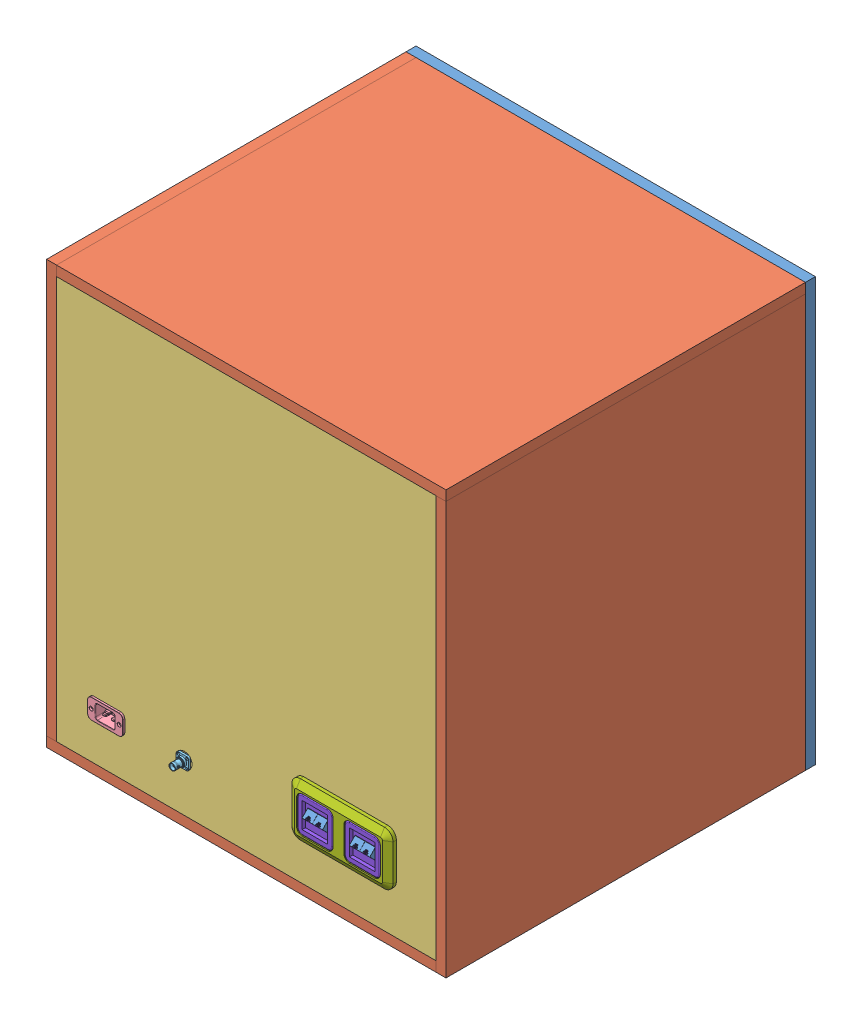
SolidWorks assembly Verlängerung, configuration Standard. Lengths in mm.
Overall size (600 635 573.25).
64 component instances, 19 part files, 30 mates.
Components (placement in the parent):
- Lochplatte-1: Lochplatte [Standard] at (-233.233 -255.3813 627.5) size (600 635 15)
- Platten-1: Platten [Standard] at (-218.233 364.6187 1182.5) x (1 0 0) z (0 1 0) size (585 540 15)
- Platten-2: Platten [Standard] at (-233.233 -255.3813 1182.5) x (1 0 0) z (0 1 0) size (585 540 15)
- Platten-3: Platten [seite] at (-218.233 -240.3813 1182.5) x (0 1 0) z (-1 0 0) size (620 540 15)
- Platten-4: Platten [seite] at (366.767 -255.3813 1182.5) x (0 1 0) z (-1 0 0) size (620 540 15)
- Back-1: Back [Standard] at (-218.233 -240.3813 1167.5) size (570 605 15)
- 17322-1: 17322 [Default] at (-142.233 -168.3813 1182.5) size (53 30 30)
- 70551600-1: 70551600 [Default] at (-26.233 -168.3813 1200.75) x (0 0 -1) z (1 0 0) size (30 18.5 18.5)
- Hohlwanddose-1: Hohlwanddose [Standard] at (180.767 -140.3813 1183.5) x (0 0 -1) z (1 0 0) size (60.7 71 71)
- Hohlwanddose-2: Hohlwanddose [Standard] at (251.767 -140.3813 1183.5) x (0 0 -1) z (1 0 0) size (60.7 71 71)
- Steckdose_2er-RJ45-1: Steckdose_2er-RJ45 [Standard] at (122.9666 -248.0462 1183.3552) size (152 80 25.23)
  - Wandplatte-1: Wandplatte [2er] at (17.3004 67.6649 10.1448) size (152 80 11)
  - Steckdose-RJ45-1: Steckdose-RJ45 [Standard] at (177.7047 18.6812 -53.8826) x (0 -1 0) z (0 0 1) size (54 54 25.23)
    - Buchse-RJ45-1: Buchse-RJ45 [Standard] at (-88.9836 -48.9043 64.0274) size (54 54 6.5)
    - 65864-1: 65864 [Default] at (-88.8386 -41.2043 53.1274) size (17.49 15.42 25.23)
      - 65864_01-1: 65864_01 [Default] at origin size (9.69 0.75 13.83)
      - 65864_02-1: 65864_02 [Default] at origin size (9.44 0.68 13.83)
      - 65864_03-1: 65864_03 [Default] at origin size (9.69 0.61 13.84)
      - 65864_04-1: 65864_04 [Default] at origin size (9.44 0.54 13.83)
      - 65864_05-1: 65864_05 [Default] at origin size (9.69 0.54 13.82)
      - 65864_06-1: 65864_06 [Default] at origin size (9.44 0.6 13.83)
      - 65864_07-1: 65864_07 [Default] at origin size (9.69 0.68 13.83)
      - 65864_08-1: 65864_08 [Default] at origin size (9.44 0.75 13.83)
      - 65864_09-1: 65864_09 [Default] at origin size (17.11 15.1 23.65)
      - 65864_10-1: 65864_10 [Default] at origin size (6.36 10.31 6.36)
      - 65864_11-1: 65864_11 [Default] at origin size (17.49 15.42 25.23)
    - 65864-2: 65864 [Default] at (-88.8386 -56.6043 53.1274) size (17.49 15.42 25.23)
      - 65864_01-1: 65864_01 [Default] at origin size (9.69 0.75 13.83)
      - 65864_02-1: 65864_02 [Default] at origin size (9.44 0.68 13.83)
      - 65864_03-1: 65864_03 [Default] at origin size (9.69 0.61 13.84)
      - 65864_04-1: 65864_04 [Default] at origin size (9.44 0.54 13.83)
      - 65864_05-1: 65864_05 [Default] at origin size (9.69 0.54 13.82)
      - 65864_06-1: 65864_06 [Default] at origin size (9.44 0.6 13.83)
      - 65864_07-1: 65864_07 [Default] at origin size (9.69 0.68 13.83)
      - 65864_08-1: 65864_08 [Default] at origin size (9.44 0.75 13.83)
      - 65864_09-1: 65864_09 [Default] at origin size (17.11 15.1 23.65)
      - 65864_10-1: 65864_10 [Default] at origin size (6.36 10.31 6.36)
      - 65864_11-1: 65864_11 [Default] at origin size (17.49 15.42 25.23)
  - Steckdose-RJ45-2: Steckdose-RJ45 [Standard] at (106.7047 18.6812 -53.8826) x (0 -1 0) z (0 0 1) size (54 54 25.23)
    - Buchse-RJ45-1: Buchse-RJ45 [Standard] at (-88.9836 -48.9043 64.0274) size (54 54 6.5)
    - 65864-1: 65864 [Default] at (-88.8386 -41.2043 53.1274) size (17.49 15.42 25.23)
      - 65864_01-1: 65864_01 [Default] at origin size (9.69 0.75 13.83)
      - 65864_02-1: 65864_02 [Default] at origin size (9.44 0.68 13.83)
      - 65864_03-1: 65864_03 [Default] at origin size (9.69 0.61 13.84)
      - 65864_04-1: 65864_04 [Default] at origin size (9.44 0.54 13.83)
      - 65864_05-1: 65864_05 [Default] at origin size (9.69 0.54 13.82)
      - 65864_06-1: 65864_06 [Default] at origin size (9.44 0.6 13.83)
      - 65864_07-1: 65864_07 [Default] at origin size (9.69 0.68 13.83)
      - 65864_08-1: 65864_08 [Default] at origin size (9.44 0.75 13.83)
      - 65864_09-1: 65864_09 [Default] at origin size (17.11 15.1 23.65)
      - 65864_10-1: 65864_10 [Default] at origin size (6.36 10.31 6.36)
      - 65864_11-1: 65864_11 [Default] at origin size (17.49 15.42 25.23)
    - 65864-2: 65864 [Default] at (-88.8386 -56.6043 53.1274) size (17.49 15.42 25.23)
      - 65864_01-1: 65864_01 [Default] at origin size (9.69 0.75 13.83)
      - 65864_02-1: 65864_02 [Default] at origin size (9.44 0.68 13.83)
      - 65864_03-1: 65864_03 [Default] at origin size (9.69 0.61 13.84)
      - 65864_04-1: 65864_04 [Default] at origin size (9.44 0.54 13.83)
      - 65864_05-1: 65864_05 [Default] at origin size (9.69 0.54 13.82)
      - 65864_06-1: 65864_06 [Default] at origin size (9.44 0.6 13.83)
      - 65864_07-1: 65864_07 [Default] at origin size (9.69 0.68 13.83)
      - 65864_08-1: 65864_08 [Default] at origin size (9.44 0.75 13.83)
      - 65864_09-1: 65864_09 [Default] at origin size (17.11 15.1 23.65)
      - 65864_10-1: 65864_10 [Default] at origin size (6.36 10.31 6.36)
      - 65864_11-1: 65864_11 [Default] at origin size (17.49 15.42 25.23)
Mates (geometry in assembly coordinates):
- Deckungsgleich1: coincident anti-aligned: plane of Lochplatte-1 through (-233.233 -255.3813 642.5) normal (0 0 1); plane of Platten-1 through (-218.233 379.6187 642.5) normal (0 0 -1)
- Deckungsgleich2: coincident aligned: plane of Lochplatte-1 through (366.767 -255.3813 642.5) normal (1 0 0); plane of Platten-1 through (366.767 379.6187 642.5) normal (1 0 0)
- Deckungsgleich3: coincident aligned: plane of Lochplatte-1 through (-233.233 379.6187 642.5) normal (0 1 0); plane of Platten-1 through (-218.233 379.6187 1182.5) normal (0 1 0)
- Deckungsgleich4: coincident anti-aligned: plane of Lochplatte-1 through (-233.233 -255.3813 642.5) normal (0 0 1); plane of Platten-2 through (-233.233 -240.3813 642.5) normal (0 0 -1)
- Deckungsgleich5: coincident aligned: plane of Lochplatte-1 through (-233.233 -255.3813 642.5) normal (-1 0 0); plane of Platten-2 through (-233.233 -240.3813 642.5) normal (-1 0 0)
- Deckungsgleich6: coincident aligned: plane of Lochplatte-1 through (-233.233 -255.3813 642.5) normal (0 -1 0); plane of Platten-2 through (-233.233 -255.3813 1182.5) normal (0 -1 0)
- Deckungsgleich7: coincident anti-aligned: plane of Lochplatte-1 through (-233.233 -255.3813 642.5) normal (0 0 1); plane of Platten-3 through (-233.233 -240.3813 642.5) normal (0 0 -1)
- Deckungsgleich8: coincident aligned: plane of Lochplatte-1 through (-233.233 -255.3813 642.5) normal (-1 0 0); plane of Platten-3 through (-233.233 -240.3813 1182.5) normal (-1 0 0)
- Deckungsgleich9: coincident aligned: plane of Platten-1 through (-218.233 379.6187 1182.5) normal (0 1 0); plane of Platten-3 through (-233.233 379.6187 642.5) normal (0 1 0)
- Deckungsgleich10: coincident anti-aligned: plane of Lochplatte-1 through (-233.233 -255.3813 642.5) normal (0 0 1); plane of Platten-4 through (351.767 -255.3813 642.5) normal (0 0 -1)
- Deckungsgleich11: coincident anti-aligned: plane of Platten-1 through (-218.233 364.6187 1182.5) normal (0 -1 0); plane of Platten-4 through (351.767 364.6187 642.5) normal (0 1 0)
- Deckungsgleich12: coincident aligned: plane of Lochplatte-1 through (366.767 -255.3813 642.5) normal (1 0 0); plane of Platten-4 through (366.767 -255.3813 1182.5) normal (1 0 0)
- Deckungsgleich13: coincident anti-aligned: plane of Platten-1 through (-218.233 364.6187 1182.5) normal (0 -1 0); plane of Back-1 through (-218.233 364.6187 1182.5) normal (0 1 0)
- Deckungsgleich14: coincident anti-aligned: plane of Platten-3 through (-218.233 -240.3813 1182.5) normal (1 0 0); plane of Back-1 through (-218.233 -240.3813 1182.5) normal (-1 0 0)
- Deckungsgleich15: coincident aligned: plane of Platten-1 through (-218.233 379.6187 1182.5) normal (0 0 1); plane of Back-1 through (-218.233 -240.3813 1182.5) normal (0 0 1)
- Deckungsgleich16: coincident anti-aligned: plane of Back-1 through (-218.233 -240.3813 1182.5) normal (0 0 1); plane of 70551600-1 through (-17.983 -174.7313 1182.5) normal (0 0 -1)
- Konzentrisch1: concentric anti-aligned: cylinder of Back-1 through (-26.233 -168.3813 1162.5) axis (0 0 1) radius 11.5; cylinder of 70551600-1 through (-26.233 -168.3813 1179.3) axis (0 0 -1) radius 5.6
- Parallel1: parallel aligned: plane of Platten-2 through (-233.233 -255.3813 1182.5) normal (0 -1 0); plane of 70551600-1 through (-19.883 -177.6313 1188.7) normal (0 -1 0)
- Deckungsgleich18: coincident anti-aligned: plane of Back-1 through (-126.233 -156.3813 1162.5) normal (-1 0 0); plane of 17322-1 through (-126.233 -176.2813 1164.5) normal (1 0 0)
- Deckungsgleich19: coincident anti-aligned: plane of Back-1 through (-158.233 -156.3813 1162.5) normal (0 -1 0); plane of 17322-1 through (-130.333 -156.3813 1164.5) normal (0 1 0)
- Deckungsgleich20: coincident anti-aligned: plane of Back-1 through (-218.233 -240.3813 1182.5) normal (0 0 1); plane of 17322-1 through (-162.733 -177.3813 1182.5) normal (0 0 -1)
- Konzentrisch2: concentric aligned: cylinder of Back-1 through (180.767 -140.3813 1162.5) axis (0 0 1) radius 34; cylinder of Hohlwanddose-1 through (180.767 -140.3813 1157) axis (0 0 1) radius 33.5
- Konzentrisch3: concentric aligned: cylinder of Back-1 through (251.767 -140.3813 1162.5) axis (0 0 1) radius 34; cylinder of Hohlwanddose-2 through (251.767 -140.3813 1157) axis (0 0 1) radius 33.5
- Parallel2: parallel aligned: plane of Platten-4 through (366.767 -255.3813 1182.5) normal (1 0 0); plane of Hohlwanddose-2 through (224.7863 -146.3813 1155.5) normal (1 0 0)
- Parallel3: parallel aligned: plane of Hohlwanddose-1 through (153.7863 -146.3813 1155.5) normal (1 0 0); plane of Hohlwanddose-2 through (224.7863 -146.3813 1155.5) normal (1 0 0)
- Deckungsgleich23: coincident anti-aligned: plane of Back-1 through (-218.233 -240.3813 1182.5) normal (0 0 1); plane of Hohlwanddose-2 through (251.767 -105.8813 1182.5) normal (0 0 -1)
- Deckungsgleich24: coincident anti-aligned: plane of Back-1 through (-218.233 -240.3813 1182.5) normal (0 0 1); plane of Hohlwanddose-1 through (180.767 -105.8813 1182.5) normal (0 0 -1)
- Konzentrisch4: concentric anti-aligned: cylinder of Hohlwanddose-2 through (251.767 -140.3813 1157) axis (0 0 1) radius 32.5; circle of Steckdose_2er-RJ45-1/Steckdose-RJ45-1/Buchse-RJ45-1
- Konzentrisch5: concentric anti-aligned: cylinder of Hohlwanddose-1 through (180.767 -140.3813 1157) axis (0 0 1) radius 32.5; circle of Steckdose_2er-RJ45-1/Steckdose-RJ45-2/Buchse-RJ45-1
- Deckungsgleich25: coincident anti-aligned: plane of Back-1 through (-218.233 -240.3813 1182.5) normal (0 0 1); plane of Steckdose_2er-RJ45-1/Wandplatte-1 through (153.067 -167.5813 1182.5) normal (0 0 -1)
